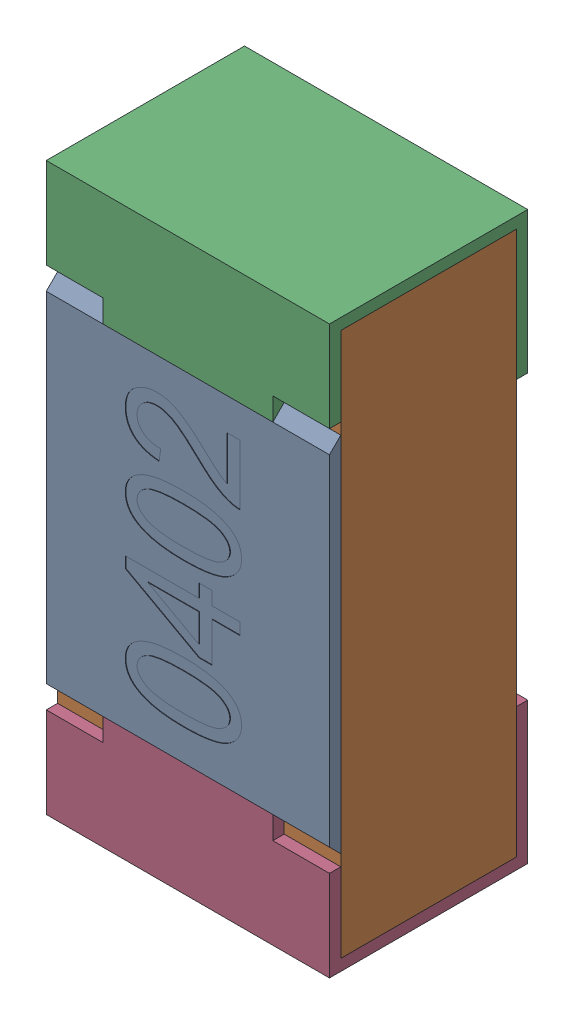
SolidWorks assembly R18, configuration Standard. Lengths in mm.
Overall size (0.5 1 0.35).
5 component instances, 4 part files, 0 mates.
Components (placement in the parent):
- R18-subassembly-1-1: R18-subassembly-1 [Standard] at (-14.5 -15.3999 0) x (0 1 0) z (0 0 1) size (1 0.5 0.35)
  - User Library-R_0402-1: User Library-R_0402 [Standard] at origin size (0.64 0.5 0.02)
  - User Library-R_0402-1-1: User Library-R_0402-1 [Standard] at origin size (0.96 0.5 0.31)
  - User Library-R_0402-2-1: User Library-R_0402-2 [Standard] at origin size (0.25 0.5 0.35)
  - User Library-R_0402-3-1: User Library-R_0402-3 [Standard] at origin size (0.25 0.5 0.35)
